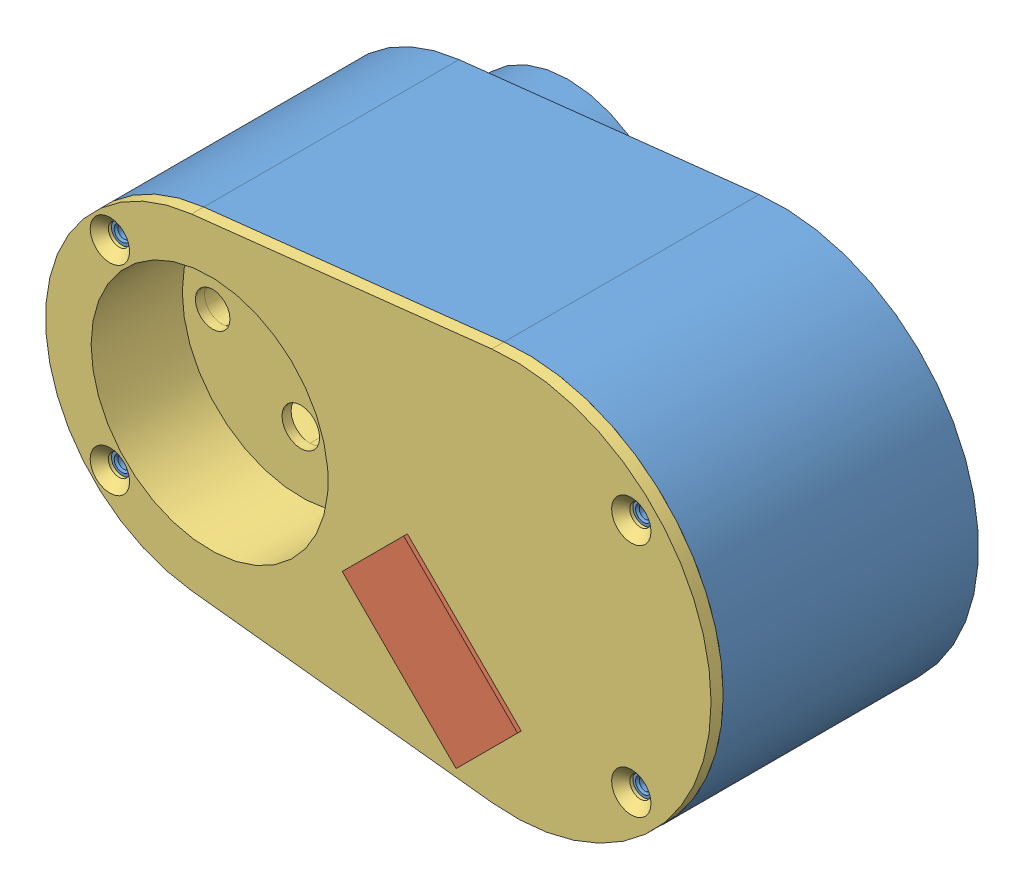
SolidWorks assembly Assemblage1, configuration Défaut. Lengths in mm.
Overall size (114.52 80.14 59.6).
5 component instances, 4 part files, 7 mates.
Components (placement in the parent):
- prise_domo_v2-1: prise_domo_v2 [Défaut] at (-35 -0.798 0) size (109.5 65 57)
- esp8266_test_board-1: esp8266_test_board [Défaut] at (12.583 -1.3951 16) x (-0.707107 0.707107 0) z (0 0 -1) size (62 51.33 42.6)
  - Pad003-1: Pad003 [Défaut] at (-71 65.5 0) size (62 51.33 42.6)
- prise_domo_2_v2-1: prise_domo_2_v2 [Défaut] at (-35 -0.798 29) size (109.5 65 41.8)
- fixsation_mall-1: fixsation_mall [Défaut] at (-35 -0.798 -3) x (0 1 0) z (0 0 1) size (31.5 32.2 5)
Mates (geometry in assembly coordinates):
- Coïncidente3: coincident anti-aligned: plane of prise_domo_v2-1 through (-35 -0.798 2) normal (0 0 1); plane of esp8266_test_board-1/Pad003-1 through (11.8223 -24.4314 2) normal (0 0 -1)
- Parallèle4: parallel: line of prise_domo_v2-1 through (15 30.102 42) axis (-1 0 0); line of esp8266_test_board-1/Pad003-1 through (20.7148 -27.2045 17.6) axis (-1 0 0)
- Coïncidente6: coincident aligned: plane of prise_domo_v2-1 through (-35 -0.798 0) normal (1 0 0); plane of prise_domo_2_v2-1 through (-35 -0.798 29) normal (1 0 0)
- Coaxiale1: concentric: cylinder of prise_domo_v2-1 through (-35 -0.798 2) axis (0 0 -1) radius 32.5; circle of prise_domo_2_v2-1
- Parallèle5: parallel anti-aligned: plane of prise_domo_v2-1 through (-18.2838 -3.798 8.0828) normal (-1 0 0); plane of fixsation_mall-1 through (-18.5 1.952 8.2578) normal (1 0 0)
- Coïncidente8: coincident anti-aligned: plane of prise_domo_v2-1 through (-35 -0.798 -3) normal (0 0 1); plane of fixsation_mall-1 through (-35 -0.798 -3) normal (0 0 -1)
- Coaxiale2: concentric anti-aligned: cylinder of prise_domo_v2-1 through (-35 -0.798 -60.2548) axis (0 0 1) radius 16; cylinder of fixsation_mall-1 through (-35 -0.798 2) axis (0 0 -1) radius 15.75
